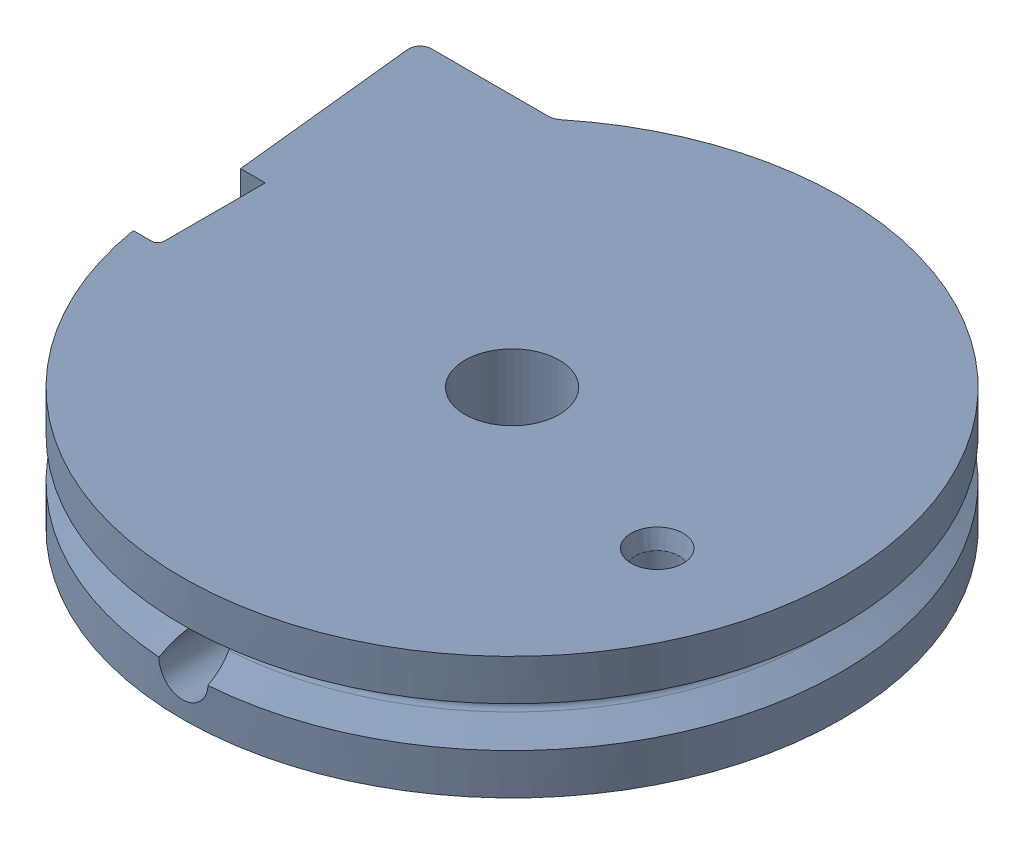
SolidWorks assembly fixed_half_pulley_with_insert, configuration Default. Lengths in mm.
Overall size (44 8 43).
2 component instances, 2 part files, 0 mates.
Components (placement in the parent):
- half-pulley_Fixed Half-Pulley-1: half-pulley_Fixed Half-Pulley [Default] at (12.3927 18.0247 32.5221) size (44 8 43)
- m3_heat_set_insert_94180A331_94180A331-1: m3_heat_set_insert_94180A331_94180A331 [Default] at (-7.2105 22.0247 32.5221) x (0 -0.064302 0.99793) z (0 -0.99793 -0.064302) size (5.56 3.88 5.56)
